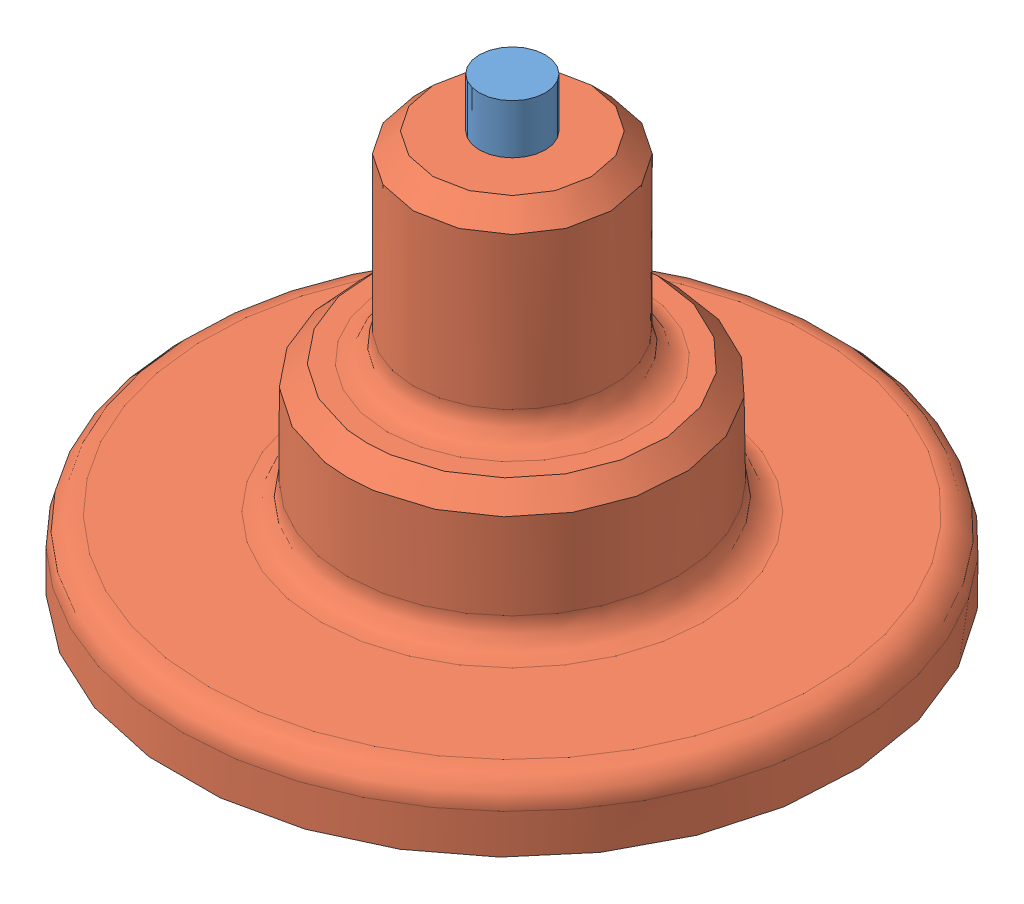
SolidWorks assembly Assem2, configuration Default. Lengths in mm.
Overall size (200 150 200).
2 component instances, 2 part files, 2 mates.
Components (placement in the parent):
- Second Pice for Revolve Piece-2: Second Pice for Revolve Piece [Default] at (11.3125 50.4129 157.6453) size (20 150 20)
- Revolve Piece-2: Revolve Piece [Default] at (21.3125 65.4129 157.6453) size (200 120 200)
Mates (geometry in assembly coordinates):
- Concentric3: concentric aligned: cylinder of Second Pice for Revolve Piece-2 through (11.3125 200.4129 157.6453) axis (0 -1 0) radius 10; cylinder of Revolve Piece-2 through (11.3125 65.4129 157.6453) axis (0 -1 0) radius 10
- Distance3: distance = 15 mm aligned: plane of Second Pice for Revolve Piece-2 through (11.3125 50.4129 157.6453) normal (0 -1 0); plane of Revolve Piece-2 through (111.3125 65.4129 157.6453) normal (0 -1 0)
